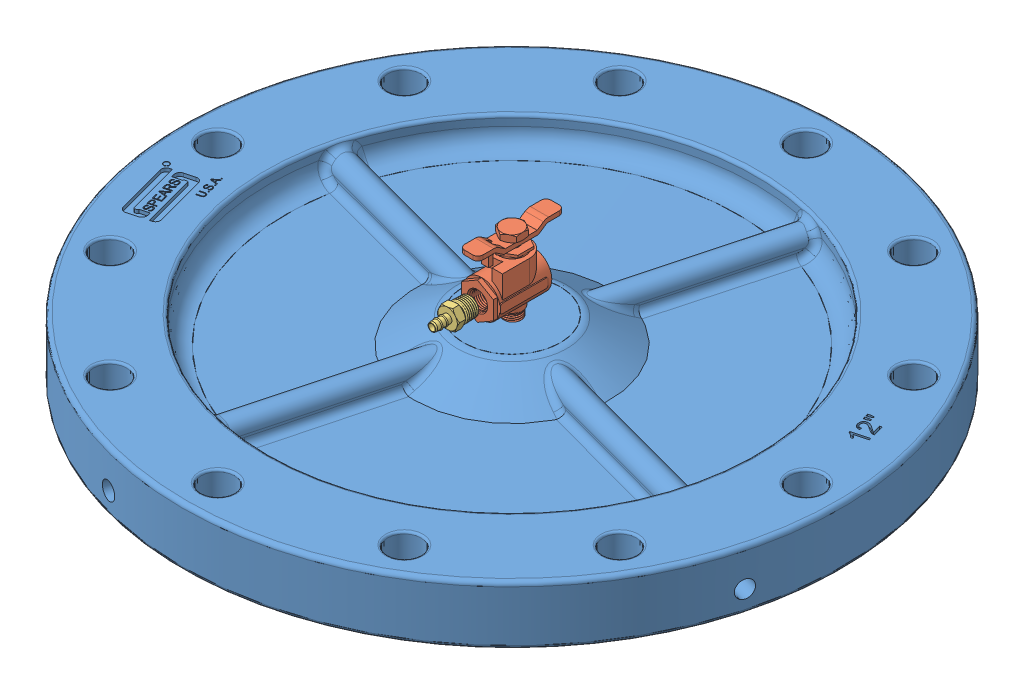
SolidWorks assembly Pressurizing Endcap BallValve, configuration Default. Lengths in mm.
Overall size (483.62 100.3 483.62).
3 component instances, 3 part files, 7 mates.
Components (placement in the parent):
- SPEARS 3D SC80-853-120-bored-1: SPEARS 3D SC80-853-120-bored [OEM part no ctr cut] x (0 1 0) z (0 0 1) size (45.16 483.62 483.62)
- 4847K140_ELBOW BRASS BALL VALVE-1: 4847K140_ELBOW BRASS BALL VALVE [4847K14] at (0 63.0428 25.3746) size (27.69 62.53 63.5)
- 44555K132_BRASS BARBED TUBE FITTING FOR VACUUM-1: 44555K132_BRASS BARBED TUBE FITTING FOR VACUUM [44555K132] at (0 63.0428 44.4485) x (0 0 -1) z (0.800936 0.59875 0) size (29.94 20.48 14.93)
Mates (geometry in assembly coordinates):
- Coincident1: coincident anti-aligned: plane of SPEARS 3D SC80-853-120-bored-1 through (-241.808 0 0) normal (0 -1 0); plane of assembly through (0 0 0) normal (0 1 0)
- Coincident2: coincident aligned: plane of SPEARS 3D SC80-853-120-bored-1 through (0 0 0) normal (0 0 1); plane of assembly through (0 0 0) normal (0 0 1)
- Coincident3: coincident anti-aligned: plane of SPEARS 3D SC80-853-120-bored-1; plane of assembly through (0 0 0) normal (1 0 0)
- Coincident4: coincident aligned: axis of SPEARS 3D SC80-853-120-bored-1 through (143.0232 0 76.1691) axis (0 0 -1); axis of 4847K140_ELBOW BRASS BALL VALVE-1 through (9.7445 0 46.666) axis (0 0 -1)
- Distance1: distance = 6.35 mm anti-aligned: plane of SPEARS 3D SC80-853-120-bored-1 through (-35.5478 41.7068 0) normal (0 1 0); plane of 4847K140_ELBOW BRASS BALL VALVE-1 through (0 48.0568 7.7153) normal (0 -1 0)
- Coincident5: coincident aligned: axis of 4847K140_ELBOW BRASS BALL VALVE-1 through (0 63.0428 22.2028) axis (0 0 -1); line of 44555K132_BRASS BARBED TUBE FITTING FOR VACUUM-1 through (0 63.0428 58.7995) axis (0 0 -1)
- Parallel1: parallel aligned: plane of 4847K140_ELBOW BRASS BALL VALVE-1 through (0 63.0428 25.3746) normal (0 0 1); plane of assembly through (0 0 0) normal (0 0 1)
